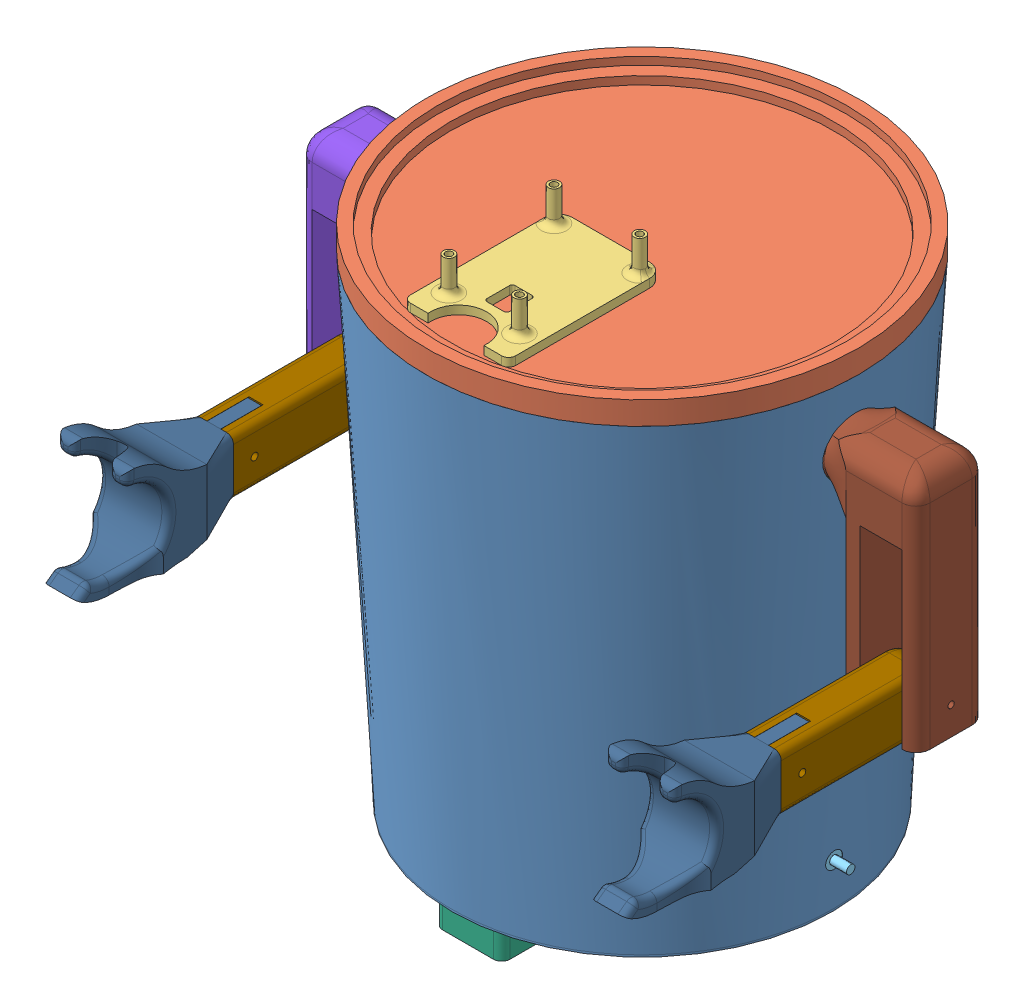
SolidWorks assembly Montagem_final, configuration Valor predeterminado. Lengths in mm.
Overall size (442.99 407.68 374.69).
22 component instances, 11 part files, 6 mates.
Components (placement in the parent):
- base_link-1: base_link [Valor predeterminado] at origin size (309.11 407.68 309.11)
  - corpo-1: corpo [Valor predeterminado] at origin size (307.81 340.4 307.81)
  - tampa-1: tampa [Valor predeterminado] at (0 339 0) x (0.003598 0 0.999994) z (-0.999994 0 0.003598) size (308 16.4 308)
  - Plataforma Lidar-1: Plataforma Lidar [Valor predeterminado] at (0 356.28 128.9319) x (0 0 1) z (-1 0 0) size (110.46 30 75)
  - Montagem_motor-1: Montagem_motor [Valor predeterminado] at (5.3444 13.461 11.8318) x (0 0 1) z (-1 0 0) size (70 44 95)
    - Capa para o motor-1: Capa para o motor [Valor predeterminado] at (-31.8318 -13.461 70.9319) size (70 44 68.53)
    - motor-1: motor [Valor predeterminado] at (-11.8318 10.539 135.8679) size (37 37 95)
  - Montagem_motor-2: Montagem_motor [Valor predeterminado] at (-5.3452 13.461 -11.8234) x (-0.000059 0 -1) z (1 0 -0.000059) size (70 44 95)
    - Capa para o motor-1: Capa para o motor [Valor predeterminado] at (-31.8318 -13.461 70.9319) size (70 44 68.53)
    - motor-1: motor [Valor predeterminado] at (-11.8318 10.539 135.8679) size (37 37 95)
  - suporte_caster-1: suporte_caster [Valor predeterminado] at (0 -1.4 -100) x (1 0 0) z (0 -1 0) size (48 48 26)
  - suporte_caster-2: suporte_caster [Valor predeterminado] at (0 -1.4 100) x (1 0 0) z (0 -1 0) size (48 48 26)
  - Plataforma-1: Plataforma [Valor predeterminado] at (-1.07 38.9294 123.9851) size (26.18 86.84 114)
  - Plataforma-2: Plataforma [Valor predeterminado] at (1.07 38.9294 -123.9851) x (-1 0 0) z (0 0 -1) size (26.18 86.84 114)
- Montagem_braco-1: Montagem_braco [Valor predeterminado] at (-207.4923 226.4656 -158.357) size (121.5 183.78 245.15)
  - Braço-2: Braço [Valor predeterminado] at (37.4923 -77.9656 133.357) x (0 1 0) z (0 0 1) size (168.75 120 50.02)
  - antebraço 2-1: antebraço 2 [Valor predeterminado] at (26.4923 -77.9656 148.357) x (0 0 1) z (-1 0 0) size (120 40 28)
  - mão versao 2-1: mão versao 2 [Valor predeterminado] at (37.4923 -70.0385 258.357) x (-1 0 0) z (0 0 -1) size (52.99 82 139.15)
- Montagem_braco_esquerdo-1: Montagem_braco_esquerdo [Valor predeterminado] at (159.9995 232.7407 -168.7505) size (121.5 183.78 245.15)
  - Braço invertido-1: Braço invertido [Valor predeterminado] at (-149.9995 -84.2407 143.7505) x (0 1 0) z (0 0 1) size (168.75 120 50.02)
  - antebraço 2-1: antebraço 2 [Valor predeterminado] at (21.0005 -44.2407 158.7505) x (0 0 1) z (1 0 0) size (120 40 28)
  - mão versao 2-1: mão versao 2 [Valor predeterminado] at (60.0005 -76.3136 268.7505) x (-1 0 0) z (0 0 -1) size (52.99 82 139.15)
Mates (geometry in assembly coordinates):
- Concêntrico1: concentric aligned: cylinder of base_link-1/Plataforma-1 through (-151.8971 294 0) axis (1 0 0) radius 21; cylinder of Montagem_braco-1/Braço-2 through (-240.6907 294 0) axis (1 0 0) radius 20.4
- Paralelo1: parallel anti-aligned: plane of Montagem_braco-1/Braço-2 through (-240.6907 148.5 25) normal (0 -1 0)
- Concêntrico2: concentric aligned: cylinder of base_link-1/Plataforma-2 through (151.8971 294 0) axis (-1 0 0) radius 21; cylinder of Montagem_braco_esquerdo-1/Braço invertido-1 through (170 294 0) axis (-1 0 0) radius 20.4
- Paralelo2: parallel anti-aligned: plane of Montagem_braco_esquerdo-1/antebraço 2-1 through (209 148.5 -10) normal (0 -1 0)
- Distância1: distance = 100 mm anti-aligned: plane of Montagem_braco_esquerdo-1/Braço invertido-1 through (100 294 0) normal (-1 0 0)
- Distância2: distance = 100 mm aligned: plane of Montagem_braco-1/Braço-2 through (-100 294 0) normal (1 0 0)
